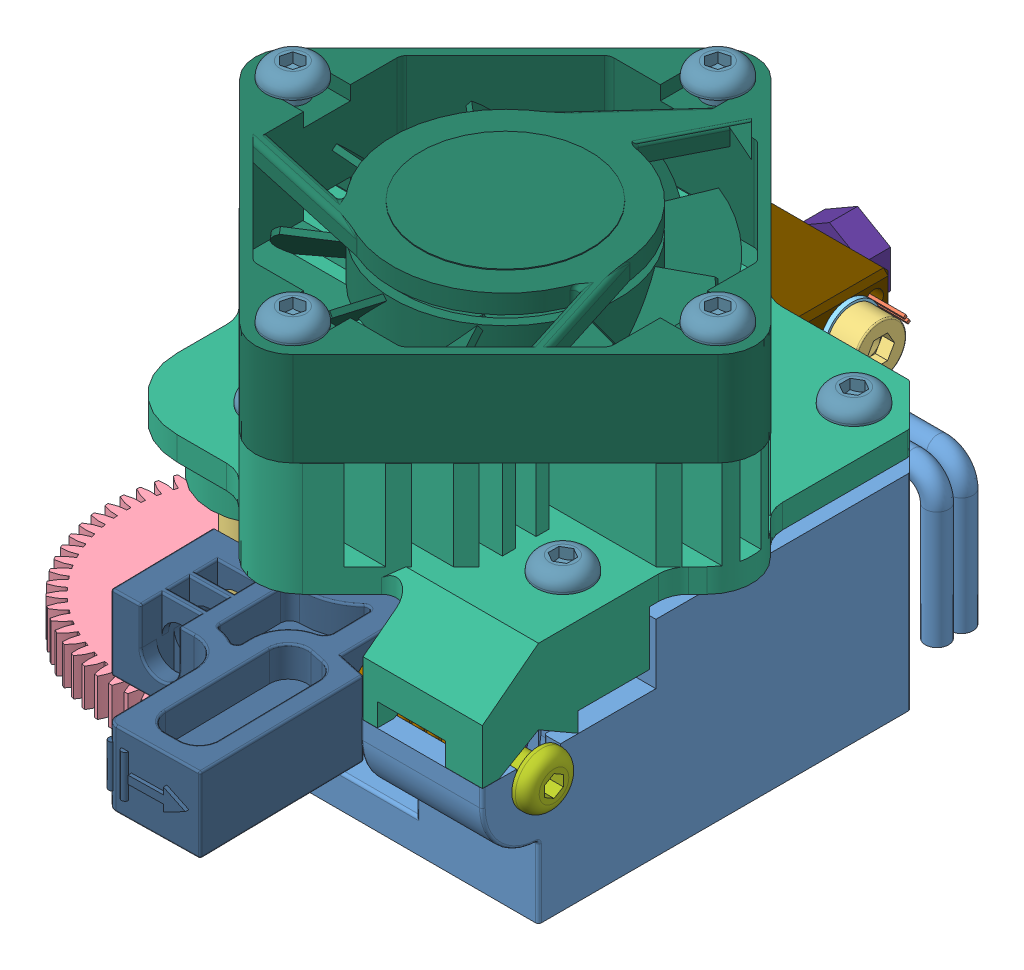
SolidWorks assembly e3d titan areo 1.751, configuration Predeterminado. Lengths in mm.
Overall size (64.29 55.52 89.93).
31 component instances, 23 part files, 0 mates.
Components (placement in the parent):
- Base-1: Base [Predeterminado] at origin size (46 23.41 49.98)
- 9x5x3mm bearing-1: 9x5x3mm bearing [Predeterminado] at (-15.5 4 15.5) x (1 0 0) z (0 -1 0) size (9 9 3)
- hobbed wheel-1: hobbed wheel [Predeterminado] at (-15.5 1.6 15.5) x (-0.447437 0 0.894315) z (0 1 0) size (8.6 8.58 20.6)
- filament gear-1: filament gear [Predeterminado] at (-15.5 8.55 15.5) x (-0.894315 0 -0.447437) z (0 -1 0) size (34 34 4)
- motor gear-1: motor gear [Predeterminado] at (0 8.5 0) x (-0.681998 0 -0.731354) z (0 -1 0) size (11.99 11.99 9)
- cover-1: cover [Predeterminado] at (0 24.9 0) x (1 0 0) z (0 0 -1) size (52.63 28.17 55.14)
- 9x5x3mm bearing-2: 9x5x3mm bearing [Predeterminado] at (-15.5 22.8 15.5) x (1 0 0) z (0 -1 0) size (9 9 3)
- m3x8-1: m3x8 [Predeterminado] at (20.7 13.6 23.3) x (0 0 1) z (0 1 0) size (5.69 9.65 5.69)
- M3 nut-1: M3 nut [Predeterminado] at (16.7 13.6 23.3) x (0 1 0) z (0 0 1) size (6.19 2.71 6.57)
- idler spring-1: idler spring [Predeterminado] at (14.287 13.6 23.3) x (0 0 1) z (-1 0 0) size (6.43 6.45 12.02)
- tensioner-1: tensioner [Predeterminado] at (0 13.6 0) x (0 -1 0) z (0.017452 0 0.999848) size (8.2 21.54 50.88)
- idler bearing pin-1: idler bearing pin [Predeterminado] at (-5.2287 9.6 15.5936) x (0.999848 0 -0.017452) z (0 1 0) size (3.04 3.15 9)
- idler bearing-1: idler bearing [Predeterminado] at (-5.2287 13.6 15.5936) x (0.999848 0 -0.017452) z (0 1 0) size (10 10 4)
- guide tube-1: guide tube [Predeterminado] at (-10.9 13.6 -7.9) x (-1 0 0) z (0 0 1) size (10.9 16.1 22.25)
- ISO 7380 - M3 x 28 v1-1: ISO 7380 - M3 x 28 v1 [Predeterminado] at (-15.5 25.94 15.5) x (0 -1 0) z (0 0 1) size (14.65 5.7 5.7)
- ISO 7380 - M3 x 28 v1-2: ISO 7380 - M3 x 28 v1 [Predeterminado] at (15.5 25.94 15.5) x (0 -1 0) z (0 0 1) size (14.65 5.7 5.7)
- ISO 7380 - M3 x 28 v1-3: ISO 7380 - M3 x 28 v1 [Predeterminado] at (15.5 25.94 -15.5) x (0 -1 0) z (0 0 1) size (14.65 5.7 5.7)
- ISO 7380 - M3 x 28 v1-4: ISO 7380 - M3 x 28 v1 [Predeterminado] at (-21.7 25.94 -14.7) x (0 -1 0) z (0 0 -1) size (14.65 5.7 5.7)
- Fan 40 X 40 X 10 v4-1: Fan 40 X 40 X 10 v4 [Predeterminado] at (-2.3 40.465 3.8274) x (0.707107 0 0.707107) z (-0.707107 0 0.707107) size (40 10.59 40)
- E3D v6 HotEnd - Heatbreak-1: E3D v6 HotEnd - Heatbreak [Predeterminado] at (-10.9 13.6 -31.7812) x (0 1 0) z (0 0 -1) size (7 7 21.9)
- E3D v6 HotEnd - Nozzle-1: E3D v6 HotEnd - Nozzle [Predeterminado] at (-10.9 13.6 -42.2812) x (0 1 0) z (0 0 -1) size (8.08 7 12.5)
- E3D v6 HotEnd - Heat Block-1: E3D v6 HotEnd - Heat Block [Predeterminado] at (-2.9 -1.9 -38.0312) x (0 1 0) z (1 0 0) size (20 11.5 16)
- Ceramic Cartridge Heater-1: Ceramic Cartridge Heater [Predeterminado] at (-0.9 6.6 -34.0312) x (0 0 1) z (1 0 0) size (6 18 29.25)
- Thermistor-1: Thermistor [Predeterminado] at (-7 16.1 -36.0312) x (0 -0.5 0.866025) z (-1 0 0) size (1.5 1.5 7.6)
- HEXAGON SOCKET HEAD CAP SCREWS_SCB3-4-1: HEXAGON SOCKET HEAD CAP SCREWS_SCB3-4 [Predeterminado] at (-2.4 14.6 -33.2312) x (0 1 0) z (1 0 0) size (5.5 5.5 7)
- HEXAGON SOCKET HEAD CAP SCREWS_SCB3-10-1: HEXAGON SOCKET HEAD CAP SCREWS_SCB3-10 [Predeterminado] at (-10.9 0.6 -38.0312) x (0 1 0) z (0 0 -1) size (5.5 5.5 13)
- Flat Washers_PWF3-1: Flat Washers_PWF3 [Predeterminado] at (-2.4 14.6 -33.2312) x (0 1 0) z (1 0 0) size (6 6 0.5)
- ISO 7380 - M3 x 28 v1-5: ISO 7380 - M3 x 28 v1 [Predeterminado] at (-2.3 45.465 26.4548) x (0 -1 0) z (0.707107 0 0.707107) size (14.65 5.7 5.7)
- ISO 7380 - M3 x 28 v1-6: ISO 7380 - M3 x 28 v1 [Predeterminado] at (-24.9274 45.465 3.8274) x (0 -1 0) z (0.707107 0 0.707107) size (14.65 5.7 5.7)
- ISO 7380 - M3 x 28 v1-7: ISO 7380 - M3 x 28 v1 [Predeterminado] at (-2.3 45.465 -18.8) x (0 -1 0) z (0.707107 0 0.707107) size (14.65 5.7 5.7)
- ISO 7380 - M3 x 28 v1-8: ISO 7380 - M3 x 28 v1 [Predeterminado] at (20.3274 45.465 3.8274) x (0 -1 0) z (0.707107 0 0.707107) size (14.65 5.7 5.7)
